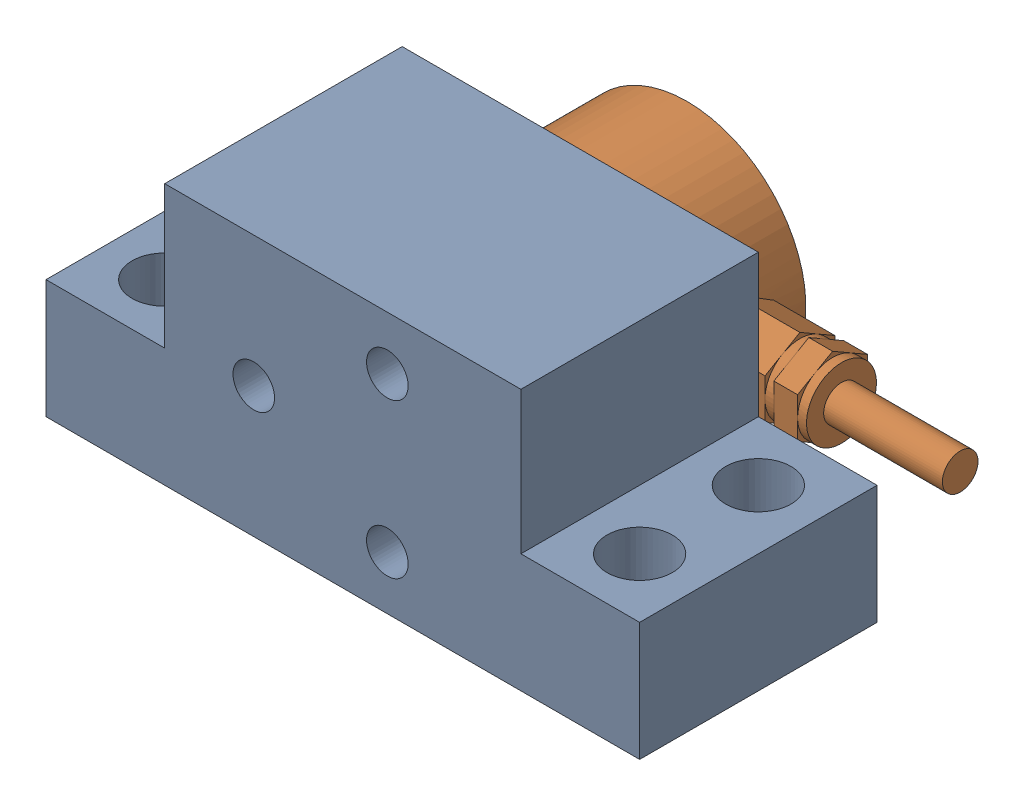
SolidWorks assembly Aynalamaloadcel yatay montaj-3, configuration Default. Lengths in mm.
Overall size (53.5 22 31).
2 component instances, 2 part files, 0 mates.
Components (placement in the parent):
- AynalamaLoadcell yatay ayak-1: AynalamaLoadcell yatay ayak [Default] at origin size (50 22 20)
- AynalamaMini_Loadcell-1: AynalamaMini_Loadcell [Default] at (0 11 -19) x (-1 0 0) z (0 -1 0) size (38.5 12 20)
